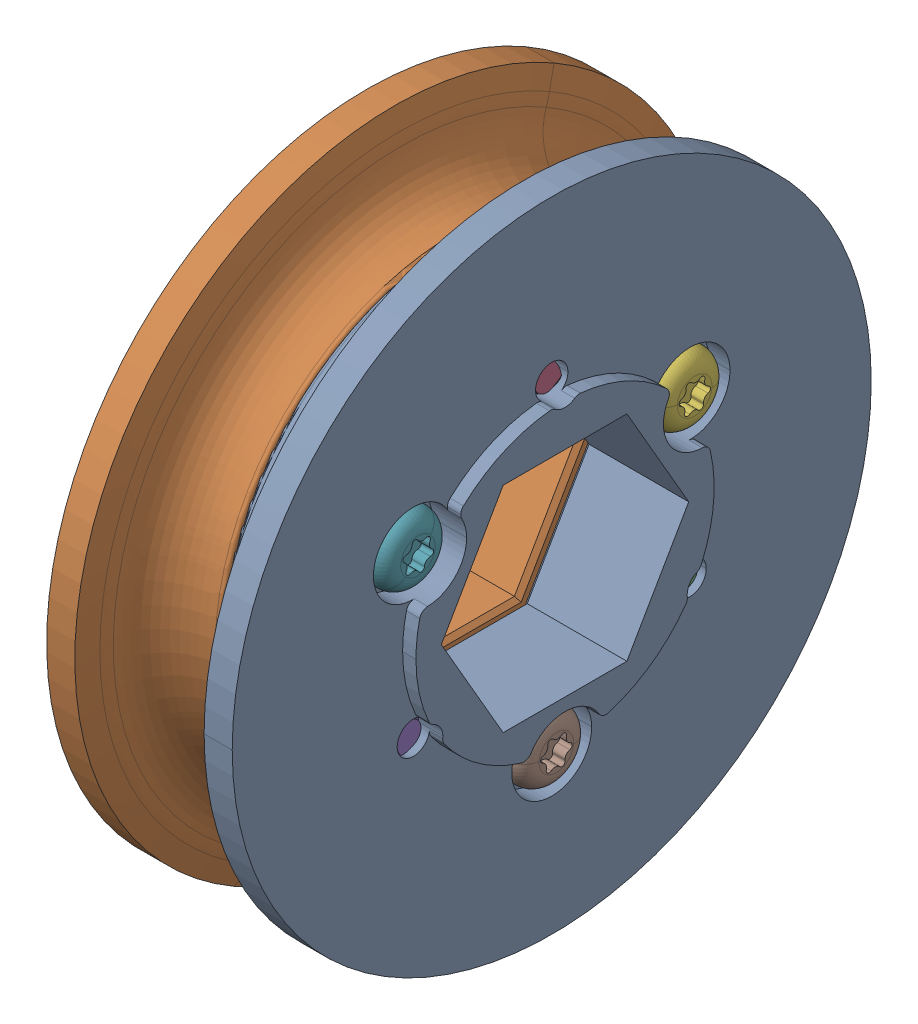
SolidWorks assembly WCP-0096 Rev6-1.step, configuration Default. Lengths in mm.
Overall size (12.65 52.05 52.05).
8 component instances, 2 part files, 0 mates.
Components (placement in the parent):
- WCP-0096-001 Rev6.step-1: WCP-0096-001 Rev6.step [Default] at origin size (7.57 38.1 38.1)
- WCP-0096-001 Rev6.step-2: WCP-0096-001 Rev6.step [Default] x (-1 0 0) z (0 0.866025 -0.5) size (7.57 38.1 38.1)
- WCP-0356 Rev1.step-1: WCP-0356 Rev1.step [Default] at (0.4817 -4.7625 -8.2489) x (0 -0.126969 0.991907) z (0 -0.991907 -0.126969) size (4.06 11.05 4.06)
- WCP-0356 Rev1.step-2: WCP-0356 Rev1.step [Default] at (0.4817 9.525 0) x (0 0.866766 0.498715) z (0 -0.498715 0.866766) size (4.06 11.05 4.06)
- WCP-0356 Rev1.step-3: WCP-0356 Rev1.step [Default] at (0.4817 -4.7625 8.2489) x (0 -0.994015 -0.109248) z (0 0.109248 -0.994015) size (4.06 11.05 4.06)
- WCP-0356 Rev1.step-4: WCP-0356 Rev1.step [Default] at (-0.4817 4.7625 -8.2489) x (0 -0.997555 0.069879) z (0 0.069879 0.997555) size (4.06 11.05 4.06)
- WCP-0356 Rev1.step-5: WCP-0356 Rev1.step [Default] at (-0.4817 4.7625 8.2489) x (0 -0.7202 -0.693767) z (0 -0.693767 0.7202) size (4.06 11.05 4.06)
- WCP-0356 Rev1.step-6: WCP-0356 Rev1.step [Default] at (-0.4817 -9.525 0) x (0 -0.997555 0.069879) z (0 0.069879 0.997555) size (4.06 11.05 4.06)
